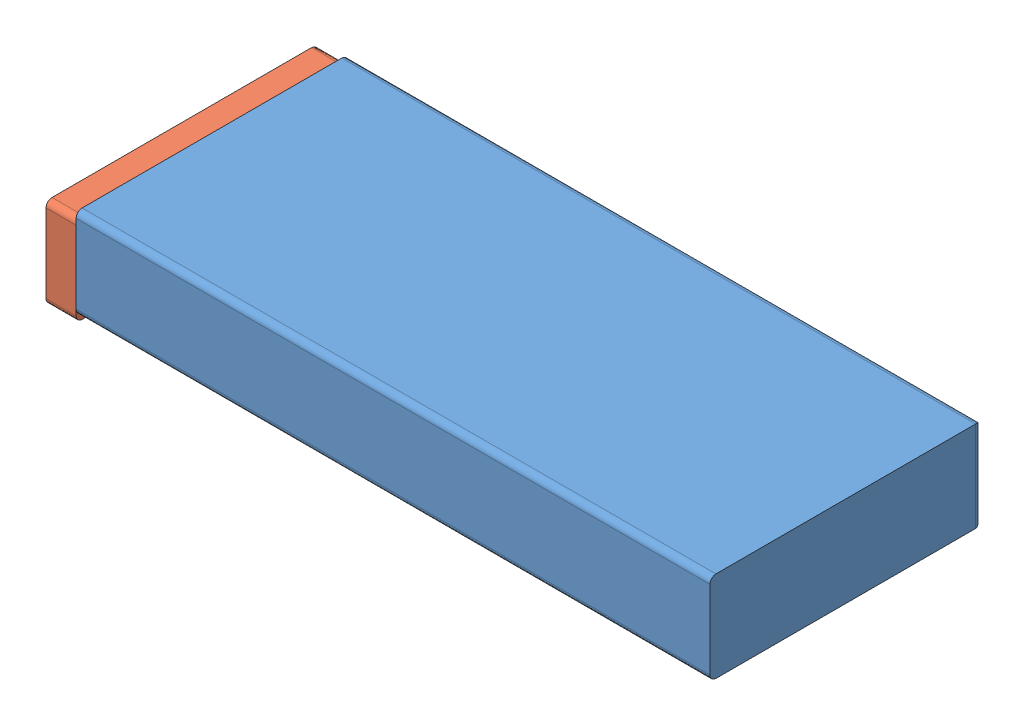
SolidWorks assembly 15, configuration Default. Lengths in mm.
Overall size (220 32.85 90.02).
4 component instances, 4 part files, 6 mates.
Components (placement in the parent):
- hộp khóa thông minh part 1-1: hộp khóa thông minh part 1 [Default] at (168.5251 -134.7374 -168.0372) size (210 30 90)
- hộp kéo-1: hộp kéo [Default] at (-40.6883 -129.162 -108.4748) x (0 0 -1) z (0 -1 0) size (90 191 30)
- khóa điện từi-1: khóa điện từi [Default] at (145.9807 -113.2374 -133.7044) x (0 1 0) z (-0.999955 0 0.00944) size (13 60.5 15)
- Arduino relay 01-1: Arduino relay 01 [Valor predeterminado] at (144.7181 -136.2374 -98.0565) x (-0.999997 0 0.002247) z (-0.002247 0 -0.999997) size (43 18.35 17.5)
Mates (geometry in assembly coordinates):
- Parallel2: parallel anti-aligned: plane of hộp khóa thông minh part 1-1 through (-30.6883 -104.7374 -85.4659) normal (-1 0 0); plane of hộp kéo-1 through (135.3117 -129.162 -108.4748) normal (1 0 0)
- Parallel3: parallel aligned: plane of hộp khóa thông minh part 1-1 through (-30.6883 -104.7374 -85.4659) normal (0 0 1); plane of hộp kéo-1 through (135.3117 -106.7374 -87.9909) normal (0 0 1)
- Coincident1: coincident anti-aligned: plane of hộp khóa thông minh part 1-1 through (-30.6883 -104.7374 -85.4659) normal (-1 0 0); plane of hộp kéo-1 through (-30.6883 -129.162 -108.4748) normal (1 0 0)
- Coincident2: coincident anti-aligned: plane of hộp khóa thông minh part 1-1 through (159.3117 -106.7374 -173.4659) normal (0 -1 0); plane of khóa điện từi-1 through (138.1978 -106.7374 -163.6323) normal (0 1 0)
- Coincident3: coincident anti-aligned: plane of hộp khóa thông minh part 1-1 through (168.5251 -134.7374 -168.0372) normal (0 -1 0); plane of Arduino relay 01-1 through (144.7181 -134.7374 -98.0565) normal (0 1 0)
- Coincident4: coincident anti-aligned: plane of hộp khóa thông minh part 1-1 through (159.3117 -106.7374 -173.4659) normal (0 -1 0); plane of hộp kéo-1 through (-30.6883 -106.7374 -85.4909) normal (0 1 0)
